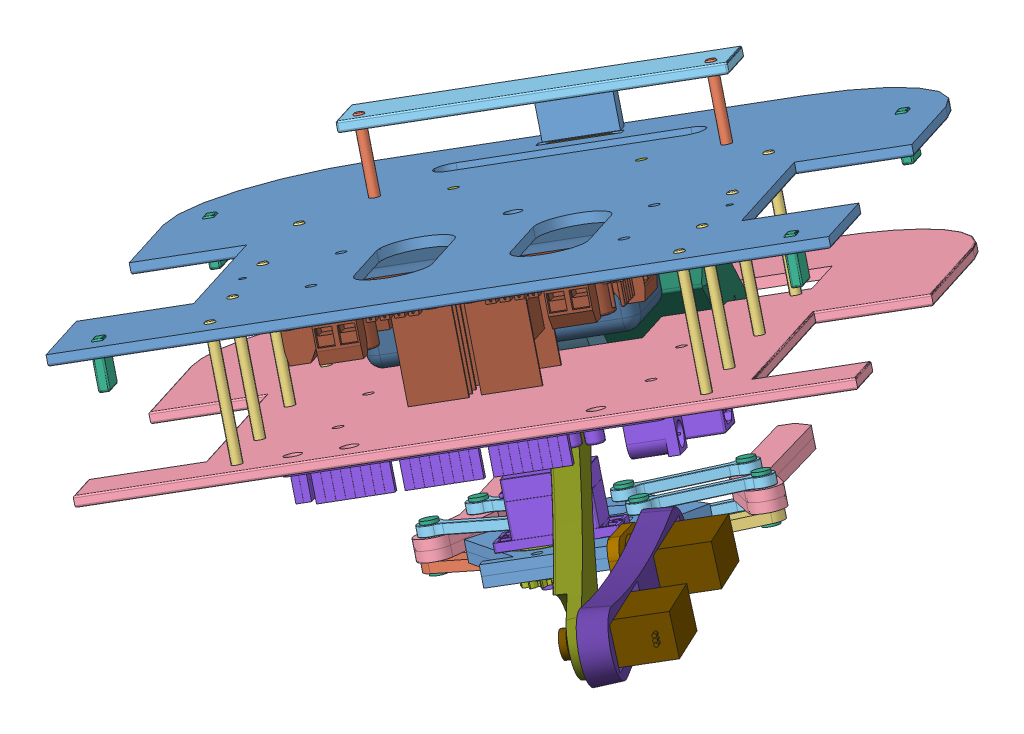
SolidWorks assembly body, configuration Default. Lengths in mm.
Overall size (305.85 281.44 329.22).
75 component instances, 27 part files, 38 mates.
Components (placement in the parent):
- Bottom-1: Bottom [Default] at (240.0196 -450.3378 91.3935) x (-0.748912 -0.245301 0.615596) z (0.507001 0.38608 0.770644) size (200 13 200)
- IR spacer-1: IR spacer [Default] at (239.1963 -439.4844 21.6169) x (0.47109 0.063028 -0.87983) z (-0.772006 -0.453054 -0.445813) size (3 25 3)
- IR spacer-3: IR spacer [Default] at (171.7942 -461.5615 77.0205) x (-0.891758 -0.383365 0.240414) z (0.150621 0.249523 0.956583) size (3 25 3)
- spacer-1: spacer [Default] at (180.6754 -475.4215 106.6688) x (-0.764646 -0.452027 -0.459335) z (-0.482946 -0.07001 0.872847) size (3 40 3)
- spacer-2: spacer [Default] at (222.0799 -492.4598 150.2506) x (0.374411 0.339543 0.86286) z (-0.823247 -0.306498 0.477832) size (3 40 3)
- spacer-3: spacer [Default] at (257.57 -465.4342 204.1957) x (0.903913 0.413434 -0.109611) z (0.029349 0.195711 0.980222) size (3 40 3)
- spacer-4: spacer [Default] at (242.3599 -477.0166 181.0764) x (0.903814 0.412806 -0.112741) z (0.032236 0.19703 0.979867) size (3 40 3)
- spacer-5: spacer [Default] at (332.2294 -447.5805 107.2049) x (-0.365654 -0.003 0.930746) z (-0.827174 -0.457407 -0.326439) size (3 40 3)
- spacer-6: spacer [Default] at (311.9493 -463.0237 76.3791) x (0.625269 0.42171 0.656658) z (-0.65342 -0.177175 0.735969) size (3 40 3)
- spacer-7: spacer [Default] at (270.5449 -445.9854 32.7973) x (-0.164362 -0.255408 -0.95276) z (-0.889328 -0.379469 0.255144) size (3 40 3)
- spacer-8: spacer [Default] at (347.4394 -435.9981 130.3242) x (-0.36301 -0.001539 0.931784) z (-0.828337 -0.457414 -0.323464) size (3 40 3)
- top final-1: top final [Default] at (255.3811 -482.3509 97.3253) x (-0.748912 -0.245301 0.615596) z (0.507001 0.38608 0.770644) size (200 13 200)
- IR panel-1: IR panel [Default] at (204.4537 -455.5657 46.0422) x (0.748912 0.245301 -0.615596) z (0.507001 0.38608 0.770644) size (100 3 20)
- t sensor-1: t sensor [Default] at (148.2719 -499.2141 101.6269) x (-0.507001 -0.38608 -0.770644) z (-0.426709 0.889252 -0.164772) size (10 3 13)
- t sensor-2: t sensor [Default] at (220.5544 -443.1963 216.7584) x (0.507001 0.38608 0.770644) z (-0.426709 0.889252 -0.164772) size (10 3 13)
- t sensor-3: t sensor [Default] at (355.3585 -399.0421 105.9511) x (-0.507001 -0.38608 -0.770644) z (-0.426709 0.889252 -0.164772) size (10 3 13)
- t sensor-4: t sensor [Default] at (278.5826 -456.5317 -5.4867) x (0.507001 0.38608 0.770644) z (-0.426709 0.889252 -0.164772) size (10 3 13)
- 6mm spacer-1: 6mm spacer [Default] at (201.415 -479.2204 71.9061) x (0.904194 0.42326 -0.057306) z (-0.018782 0.173438 0.984666) size (3 6 3)
- 6mm spacer-6: 6mm spacer [Default] at (237.3627 -467.446 42.3575) x (0.897667 0.394277 -0.196822) z (0.110059 0.231896 0.966494) size (3 6 3)
- ARDUINO MEGA-1: ARDUINO MEGA [Default] at (293.8708 -457.8048 148.3281) x (-0.748912 -0.245301 0.615596) z (0.507001 0.38608 0.770644) size (108 12.8 52)
- tcs34725-1: tcs34725 [Default] at (200.1491 -492.8286 26.0185) x (-0.748912 -0.245301 0.615596) z (0.426709 -0.889252 0.164772) size (20.3 2.67 20)
- batt-1: batt [Default] at (270.664 -428.9031 145.9212) x (0.507001 0.38608 0.770644) z (0.748912 0.245301 -0.615596) size (58.61 25 130.11)
- L298N Stepper Motor Driver Assembly-1: L298N Stepper Motor Driver Assembly [Default] at (255.5695 -426.9058 134.486) x (0.507001 0.38608 0.770644) z (0.748912 0.245301 -0.615596) size (43 28.01 43)
  - L298N Stepper Motor Driver (Red)-Part File-1: L298N Stepper Motor Driver (Red)-Part File [Default] at (16.8606 10.1012 32.1341) size (43 28.01 43)
  - pan head cross recess screw_iso_ISO 7045 - M1.6 x 4 - Z - 4N-1: pan head cross recess screw_iso_ISO 7045 - M1.6 x 4 - Z - 4N [Default] at (-1.3394 22.4012 35.9476) x (0 -1 0) z (-0.742963 0 0.669332) size (5.3 3.2 3.23)
  - pan head cross recess screw_iso_ISO 7045 - M1.6 x 4 - Z - 4N-2: pan head cross recess screw_iso_ISO 7045 - M1.6 x 4 - Z - 4N [Default] at (-1.3394 22.4012 41.5921) x (0 -1 0) z (-0.751552 0 0.659674) size (5.3 3.2 3.23)
  - pan head cross recess screw_iso_ISO 7045 - M1.6 x 4 - Z - 4N-3: pan head cross recess screw_iso_ISO 7045 - M1.6 x 4 - Z - 4N [Default] at (3.7852 22.4012 50.3107) x (0 -1 0) z (0.734198 0 -0.678936) size (5.3 3.2 3.23)
  - pan head cross recess screw_iso_ISO 7045 - M1.6 x 4 - Z - 4N-4: pan head cross recess screw_iso_ISO 7045 - M1.6 x 4 - Z - 4N [Default] at (14.2688 22.4012 50.3107) x (0 -1 0) z (0.720108 0 0.693862) size (5.3 3.2 3.23)
  - pan head cross recess screw_iso_ISO 7045 - M1.6 x 4 - Z - 4N-5: pan head cross recess screw_iso_ISO 7045 - M1.6 x 4 - Z - 4N [Default] at (9.027 22.4012 50.3107) x (0 -1 0) z (0.308372 0 0.951266) size (5.3 3.2 3.23)
  - pan head cross recess screw_iso_ISO 7045 - M1.6 x 4 - Z - 4N-6: pan head cross recess screw_iso_ISO 7045 - M1.6 x 4 - Z - 4N [Default] at (33.6606 22.4012 35.9476) x (0 -1 0) z (0 0 1) size (5.3 3.2 3.23)
  - pan head cross recess screw_iso_ISO 7045 - M1.6 x 4 - Z - 4N-7: pan head cross recess screw_iso_ISO 7045 - M1.6 x 4 - Z - 4N [Default] at (33.6606 22.4012 41.6421) x (0 -1 0) z (-0.222944 0 0.974831) size (5.3 3.2 3.23)
  - countersunk flat head cross recess screw_iso_ISO 7046-1 - M2.5 x 3 - Z - 3N-1: countersunk flat head cross recess screw_iso_ISO 7046-1 - M2.5 x 3 - Z - 3N [Default] at (16.3567 30.6012 21.6857) x (0 0 -1) z (1 0 0) size (3 4.7 4.7)
- L298N Stepper Motor Driver Assembly-2: L298N Stepper Motor Driver Assembly [Default] at (286.3475 -409.4056 149.2271) x (-0.507001 -0.38608 -0.770644) z (-0.748912 -0.245301 0.615596) size (43 28.01 43)
  - L298N Stepper Motor Driver (Red)-Part File-1: L298N Stepper Motor Driver (Red)-Part File [Default] at (16.8606 10.1012 32.1341) size (43 28.01 43)
  - pan head cross recess screw_iso_ISO 7045 - M1.6 x 4 - Z - 4N-1: pan head cross recess screw_iso_ISO 7045 - M1.6 x 4 - Z - 4N [Default] at (-1.3394 22.4012 35.9476) x (0 -1 0) z (-0.742963 0 0.669332) size (5.3 3.2 3.23)
  - pan head cross recess screw_iso_ISO 7045 - M1.6 x 4 - Z - 4N-2: pan head cross recess screw_iso_ISO 7045 - M1.6 x 4 - Z - 4N [Default] at (-1.3394 22.4012 41.5921) x (0 -1 0) z (-0.751552 0 0.659674) size (5.3 3.2 3.23)
  - pan head cross recess screw_iso_ISO 7045 - M1.6 x 4 - Z - 4N-3: pan head cross recess screw_iso_ISO 7045 - M1.6 x 4 - Z - 4N [Default] at (3.7852 22.4012 50.3107) x (0 -1 0) z (0.734198 0 -0.678936) size (5.3 3.2 3.23)
  - pan head cross recess screw_iso_ISO 7045 - M1.6 x 4 - Z - 4N-4: pan head cross recess screw_iso_ISO 7045 - M1.6 x 4 - Z - 4N [Default] at (14.2688 22.4012 50.3107) x (0 -1 0) z (0.720108 0 0.693862) size (5.3 3.2 3.23)
  - pan head cross recess screw_iso_ISO 7045 - M1.6 x 4 - Z - 4N-5: pan head cross recess screw_iso_ISO 7045 - M1.6 x 4 - Z - 4N [Default] at (9.027 22.4012 50.3107) x (0 -1 0) z (0.308372 0 0.951266) size (5.3 3.2 3.23)
  - pan head cross recess screw_iso_ISO 7045 - M1.6 x 4 - Z - 4N-6: pan head cross recess screw_iso_ISO 7045 - M1.6 x 4 - Z - 4N [Default] at (33.6606 22.4012 35.9476) x (0 -1 0) z (0 0 1) size (5.3 3.2 3.23)
  - pan head cross recess screw_iso_ISO 7045 - M1.6 x 4 - Z - 4N-7: pan head cross recess screw_iso_ISO 7045 - M1.6 x 4 - Z - 4N [Default] at (33.6606 22.4012 41.6421) x (0 -1 0) z (-0.222944 0 0.974831) size (5.3 3.2 3.23)
  - countersunk flat head cross recess screw_iso_ISO 7046-1 - M2.5 x 3 - Z - 3N-1: countersunk flat head cross recess screw_iso_ISO 7046-1 - M2.5 x 3 - Z - 3N [Default] at (16.3567 30.6012 21.6857) x (0 0 -1) z (1 0 0) size (3 4.7 4.7)
- 3D_model assem-1: 3D_model assem [Default] at (179.7767 -482.7925 -10.8406) x (-0.761134 -0.254706 0.59649) z (0.488462 0.379941 0.785525) size (132.33 120.49 215.34)
  - Waist_r1-2: Waist_r1 [Default] at (12.283 16.6911 88.1271) size (60 61.78 65.42)
  - Servo Motor MG996R_r1-1: Servo Motor MG996R_r1 [Default] at (-33.917 49.7197 81.4564) x (0 -0.707107 0.707107) z (0 0.707107 0.707107) size (55.8 47.4 20.5)
  - sub_Arm 1-1: sub_Arm 1 [Default] at (8.283 90.1315 96.5727) x (0 0.829099 0.559102) z (0 0.559102 -0.829099) size (105 8.09 20)
  - sub_Arm 2-1: sub_Arm 2 [Default] at (8.283 119.9356 85.3041) x (0 -0.09793 -0.995193) z (0 0.995193 -0.09793) size (100 8 20)
  - Servo Motor Micro  9g-1: Servo Motor Micro  9g [Default] at (-14.017 122.796 113.8613) x (0 -0.09793 -0.995193) z (0 -0.995193 0.09793) size (32.6 29.9 12.4)
  - grip_01-1: grip_01 [Default] at (31.383 116.5998 46.1646) x (1 0 0) z (0 0.999922 -0.012455) size (132.33 143.36 29.8)
    - Part3-3-1: Part3-3 [Default] at origin size (63.11 62 3)
    - part4-4-1: part4-4 [Default] at (13.5 37.5997 3) x (0 0 1) z (-0.939811 -0.341694 0) size (3 29.07 49.54)
    - part5-5-1: part5-5 [Default] at (-13.5 37.5997 6) x (0 0 -1) z (0.976371 -0.216101 0) size (3 26.63 49.27)
    - Part1-1-1: Part1-1 [Default] at (-42.6341 48.1922 0) x (0.375321 0.926895 0) z (0 0 1) size (78.8 28.36 3)
    - Part2-2-1: Part2-2 [Default] at (-5.2398 58 4.5) x (-0.939912 0.341417 0) z (0 0 1) size (38 7 3)
    - Part2-2-2: Part2-2 [Default] at (5.2398 58 4.5) x (0.939912 0.341417 0) z (0 0 1) size (38 7 3)
    - Part1-1-2: Part1-1 [Default] at (42.6341 48.1922 3) x (-0.375321 0.926895 0) z (0 0 -1) size (78.8 28.36 3)
    - Part3-3-2: Part3-3 [Default] at (0 0 -3) size (63.11 62 3)
    - Part1-1-3: Part1-1 [Default] at (42.6341 48.1922 0) x (-0.375321 0.926895 0) z (0 0 -1) size (78.8 28.36 3)
    - Part1-1-4: Part1-1 [Default] at (-42.6341 48.1922 -3) x (0.375321 0.926895 0) z (0 0 1) size (78.8 28.36 3)
    - Part2-2-5: Part2-2 [Default] at (-5.2398 58 -4.5) x (-0.939912 0.341417 0) z (0 0 1) size (38 7 3)
    - Part2-2-6: Part2-2 [Default] at (5.2398 58 -4.5) x (0.939912 0.341417 0) z (0 0 1) size (38 7 3)
    - Part2-2-9: Part2-2 [Default] at (13.5 37.5997 -4.5) x (0.939811 0.341694 0) z (0 0 1) size (38 7 3)
    - Part2-2-10: Part2-2 [Default] at (-13.5 37.5997 -4.5) x (-0.939811 0.341694 0) z (0 0 1) size (38 7 3)
    - Part6-6-1: Part6-6 [Default] at (13.5 37.5997 7) x (1 0 0) z (0 1 0) size (5 14 5)
    - Part6-6-2: Part6-6 [Default] at (-13.5 37.5997 -7) x (-0.923728 -0.383049 0) z (-0.383049 0.923728 0) size (5 14 5)
    - Part6-6-3: Part6-6 [Default] at (-42.6341 48.1922 -7) x (-0.923728 -0.383049 0) z (-0.383049 0.923728 0) size (5 14 5)
    - Part6-6-4: Part6-6 [Default] at (-5.2398 58 -7) x (0.923728 0.383049 0) z (0.383049 -0.923728 0) size (5 14 5)
    - Part6-6-5: Part6-6 [Default] at (-34.3771 68.5839 -7) x (0.923728 0.383049 0) z (0.383049 -0.923728 0) size (5 14 5)
    - Part6-6-6: Part6-6 [Default] at (34.3771 68.5839 -7) x (0.923728 0.383049 0) z (0.383049 -0.923728 0) size (5 14 5)
    - Part6-6-7: Part6-6 [Default] at (5.2398 58 -7) x (0.923728 0.383049 0) z (0.383049 -0.923728 0) size (5 14 5)
    - Part6-6-8: Part6-6 [Default] at (42.6341 48.1922 -7) x (0.923728 0.383049 0) z (0.383049 -0.923728 0) size (5 14 5)
    - part8-8-1: part8-8 [Default] at (7.5 17.5997 7) x (0 0 -1) z (0.607129 -0.794603 0) size (10.1 17.5 17.5)
    - microservoSG90-1: microservoSG90 [Default] at (2.4 17.5997 -21.2) x (-1 0 0) z (0 1 0) size (32.3 29.8 12.5)
    - help3-1: help3 [Default] at (-17 -5.5 0) x (0 -1 0) z (-1 0 0) size (25 15 3)
  - Servo Motor Micro  9g-2: Servo Motor Micro  9g [Default] at (-13.517 117.174 57.2397) x (0 0.09793 0.995193) z (0 0.995193 -0.09793) size (32.6 29.9 12.4)
Mates (geometry in assembly coordinates):
- Coincident28: coincident anti-aligned: circle of Bottom-1; circle of IR spacer-1
- Concentric13: concentric aligned: cylinder of Bottom-1 through (180.8888 -475.8661 106.7512) axis (0.426709 -0.889252 0.164772) radius 1.5; circle of spacer-1
- Coincident71: coincident anti-aligned: plane of Bottom-1 through (240.0196 -450.3378 91.3935) normal (-0.426709 0.889252 -0.164772); circle of spacer-1
- Concentric14: concentric anti-aligned: cylinder of Bottom-1 through (205.2249 -457.3343 143.7421) axis (0.426709 -0.889252 0.164772) radius 1.5; circle of spacer-2
- Coincident73: coincident anti-aligned: plane of Bottom-1 through (240.0196 -450.3378 91.3935) normal (-0.426709 0.889252 -0.164772); circle of spacer-2
- Concentric15: concentric aligned: cylinder of Bottom-1 through (240.715 -430.3088 197.6872) axis (0.426709 -0.889252 0.164772) radius 1.5; cylinder of spacer-3 through (240.5016 -429.8641 197.6048) axis (0.426709 -0.889252 0.164772) radius 1.5
- Coincident74: coincident anti-aligned: plane of Bottom-1 through (240.0196 -450.3378 91.3935) normal (-0.426709 0.889252 -0.164772); circle of spacer-3
- Coincident75: coincident aligned: cylinder of Bottom-1 through (225.5049 -441.8911 174.5679) axis (0.426709 -0.889252 0.164772) radius 1.5; circle of spacer-4
- Coincident76: coincident anti-aligned: plane of Bottom-1 through (240.0196 -450.3378 91.3935) normal (-0.426709 0.889252 -0.164772); circle of spacer-4
- Coincident85: coincident anti-aligned: circle of IR spacer-3; plane of IR panel-1 through (203.1736 -452.8979 45.5479) normal (-0.426709 0.889252 -0.164772)
- Concentric18: concentric anti-aligned: circle of IR spacer-1; circle of IR panel-1
- Concentric19: concentric anti-aligned: circle of spacer-3; cylinder of top final-1 through (256.0765 -462.3218 203.619) axis (0.426709 -0.889252 0.164772) radius 1.5
- Coincident87: coincident anti-aligned: circle of spacer-1; cylinder of top final-1 through (196.2503 -507.8792 112.683) axis (0.426709 -0.889252 0.164772) radius 1.5
- Coincident88: coincident anti-aligned: circle of spacer-3; plane of top final-1 through (256.6612 -485.0187 97.8196) normal (0.426709 -0.889252 0.164772)
- Parallel18: parallel aligned: plane of Bottom-1 through (217.1086 -438.9278 230.5118) normal (-0.748912 -0.245301 0.615596); plane of t sensor-1 through (146.0252 -499.95 103.4737) normal (-0.748912 -0.245301 0.615596)
- Coincident104: coincident anti-aligned: plane of Bottom-1 through (219.2616 -436.8956 217.6964) normal (0.748912 0.245301 -0.615596); plane of t sensor-2 through (220.5544 -443.1963 216.7584) normal (-0.748912 -0.245301 0.615596)
- Coincident105: coincident anti-aligned: plane of Bottom-1 through (218.9734 -438.0901 211.9964) normal (0.507001 0.38608 0.770644); plane of t sensor-2 through (216.5133 -438.3814 213.7608) normal (-0.507001 -0.38608 -0.770644)
- Coincident106: coincident: line of Bottom-1; line of t sensor-2 through (219.0081 -437.0887 217.311) axis (-0.507001 -0.38608 -0.770644)
- Coincident113: coincident anti-aligned: plane of Bottom-1 through (144.7324 -493.6493 104.4117) normal (-0.507001 -0.38608 -0.770644); plane of t sensor-1 through (146.7658 -492.4688 102.4825) normal (0.507001 0.38608 0.770644)
- Coincident114: coincident anti-aligned: line of Bottom-1 through (142.1974 -495.5797 100.5585) axis (0.507001 0.38608 0.770644); line of t sensor-1 through (144.4789 -493.8424 104.0264) axis (-0.507001 -0.38608 -0.770644)
- Concentric20: concentric aligned: cylinder of Bottom-1 through (195.8677 -467.6601 69.7641) axis (0.426709 -0.889252 0.164772) radius 1.5; cylinder of 6mm spacer-1 through (198.8547 -473.8849 70.9175) axis (0.426709 -0.889252 0.164772) radius 1.5
- Coincident115: coincident aligned: plane of Bottom-1 through (240.0196 -450.3378 91.3935) normal (-0.426709 0.889252 -0.164772); plane of 6mm spacer-1 through (198.8547 -473.8849 70.9175) normal (-0.426709 0.889252 -0.164772)
- Concentric22: concentric aligned: cylinder of Bottom-1 through (231.8155 -455.8857 40.2155) axis (0.426709 -0.889252 0.164772) radius 1.5; cylinder of 6mm spacer-6 through (234.8025 -462.1104 41.3689) axis (0.426709 -0.889252 0.164772) radius 1.5
- Coincident117: coincident aligned: plane of Bottom-1 through (240.0196 -450.3378 91.3935) normal (-0.426709 0.889252 -0.164772); plane of 6mm spacer-6 through (234.8025 -462.1104 41.3689) normal (-0.426709 0.889252 -0.164772)
- Concentric26: concentric anti-aligned: cylinder of IR spacer-3 through (182.4619 -483.7928 81.1398) axis (-0.426709 0.889252 -0.164772) radius 1.5; cylinder of IR panel-1 through (172.0076 -462.0061 77.1029) axis (0.426709 -0.889252 0.164772) radius 1.5
- Coincident127: coincident anti-aligned: plane of top final-1 through (256.6612 -485.0187 97.8196) normal (0.426709 -0.889252 0.164772); plane of ARDUINO MEGA-1 through (313.01 -457.8714 98.4036) normal (-0.426709 0.889252 -0.164772)
- Concentric27: concentric anti-aligned: cylinder of top final-1 through (321.108 -434.0381 145.3679) axis (0.426709 -0.889252 0.164772) radius 2.5; axis of ARDUINO MEGA-1 through (326.1431 -444.5313 147.3122) axis (-0.426709 0.889252 -0.164772)
- Parallel29: parallel aligned: plane of top final-1 through (208.5045 -511.0823 142.559) normal (-0.748912 -0.245301 0.615596); plane of ARDUINO MEGA-1 through (245.8596 -476.5069 171.7293) normal (-0.748912 -0.245301 0.615596)
- Coincident139: coincident anti-aligned: plane of Bottom-1 through (187.6724 -486.6251 31.119) normal (-0.507001 -0.38608 -0.770644); plane of tcs34725-1 through (191.2667 -488.0615 29.474) normal (0.507001 0.38608 0.770644)
- Coincident141: coincident aligned: plane of Bottom-1 through (240.0196 -450.3378 91.3935) normal (-0.426709 0.889252 -0.164772); plane of tcs34725-1 through (200.7442 -482.7068 18.4138) normal (-0.426709 0.889252 -0.164772)
- Distance7: distance = 1 mm: line of Bottom-1 through (203.9076 -485.0545 15.7583) axis (0.507001 0.38608 0.770644); line of tcs34725-1 through (203.7303 -484.3424 17.2687) axis (0.507001 0.38608 0.770644)
- Coincident144: coincident anti-aligned: plane of Bottom-1 through (241.2997 -453.0056 91.8878) normal (0.426709 -0.889252 0.164772); plane of batt-1 through (270.664 -428.9031 145.9212) normal (-0.426709 0.889252 -0.164772)
- Parallel34: parallel aligned: plane of Bottom-1 through (115.7083 -516.1437 76.383) normal (-0.507001 -0.38608 -0.770644); plane of batt-1 through (225.7498 -483.5957 118.7916) normal (-0.507001 -0.38608 -0.770644)
- Distance10: distance = 34 mm: line of Bottom-1 through (219.9239 -446.6962 181.2957) axis (-0.507001 -0.38608 -0.770644); cylinder of batt-1 through (219.7846 -463.9402 112.869) axis (-0.507001 -0.38608 -0.770644) radius 4
- Coincident146: coincident anti-aligned: plane of Bottom-1 through (241.2997 -453.0056 91.8878) normal (0.426709 -0.889252 0.164772); plane of L298N Stepper Motor Driver Assembly-1/L298N Stepper Motor Driver (Red)-Part File-1 through (292.4938 -421.4963 129.3622) normal (-0.426709 0.889252 -0.164772)
- Distance11: distance = 55 mm: line of L298N Stepper Motor Driver Assembly-1/L298N Stepper Motor Driver (Red)-Part File-1 through (297.6948 -424.5231 99.5581) axis (0.507001 0.38608 0.770644); line of Bottom-1 through (346.49 -405.2403 77.26) axis (0.507001 0.38608 0.770644)
- Distance12: distance = 11 mm: line of L298N Stepper Motor Driver Assembly-1/L298N Stepper Motor Driver (Red)-Part File-1 through (319.4959 -407.9217 132.6958) axis (-0.748912 -0.245301 0.615596); line of Bottom-1 through (366.2631 -390.1832 107.3151) axis (-0.748912 -0.245301 0.615596)
- Coincident147: coincident anti-aligned: plane of Bottom-1 through (241.2997 -453.0056 91.8878) normal (0.426709 -0.889252 0.164772); plane of 3D_model assem-1/Waist_r1-2 through (220.5966 -467.2806 68.4623) normal (-0.426709 0.889252 -0.164772)
